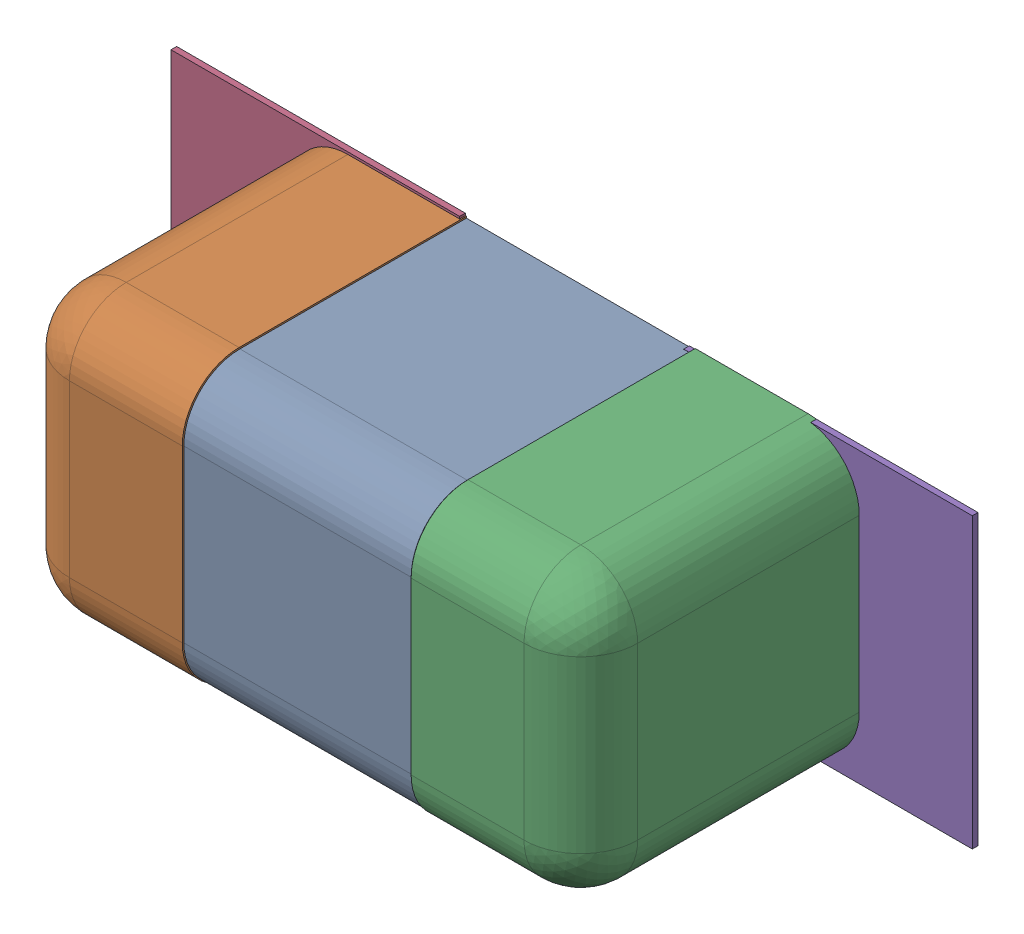
SolidWorks assembly C57, configuration Défaut. Lengths in mm.
Overall size (1.41 0.51 0.5).
8 component instances, 4 part files, 0 mates.
Components (placement in the parent):
- 6324936752-1: 6324936752 [Défaut] at (7.5083 -18.453 0) x (1 0 0) z (0 -1 0) size (1 0.5 0.5)
  - Open CASCADE STEP translator 7.5 2.114.1.1-1: Open CASCADE STEP translator 7.5 2.114.1.1 [Défaut] at origin size (0.4 0.5 0.5)
  - Open CASCADE STEP translator 7.5 2.114.1.2-1: Open CASCADE STEP translator 7.5 2.114.1.2 [Défaut] at origin size (0.3 0.5 0.5)
  - Open CASCADE STEP translator 7.5 2.114.1.3-1: Open CASCADE STEP translator 7.5 2.114.1.3 [Défaut] at origin size (0.3 0.5 0.5)
- 6504207776-1: 6504207776 [Défaut] at (7.051 -18.453 0) size (0.51 0.51 0.01)
  - Extruded-1: Extruded [Défaut] at origin size (0.51 0.51 0.01)
- 6504207776-2: 6504207776 [Défaut] at (7.9533 -18.4582 0) size (0.51 0.51 0.01)
  - Extruded-1: Extruded [Défaut] at origin size (0.51 0.51 0.01)
